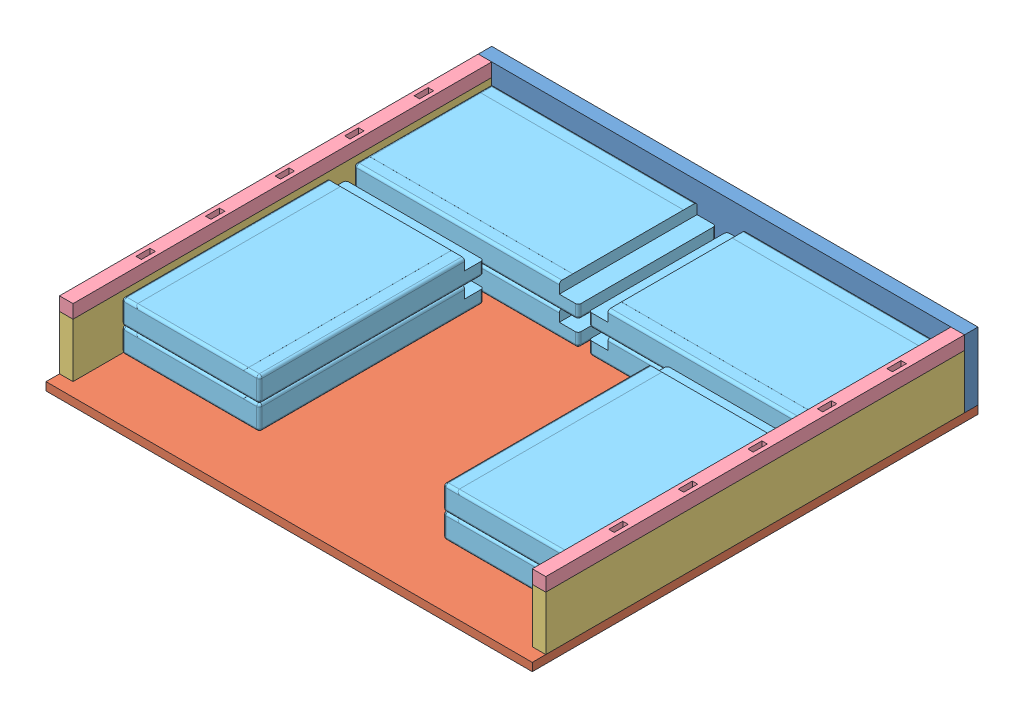
SolidWorks assembly Assem1, configuration Default. Lengths in mm.
Overall size (180 28 165).
14 component instances, 5 part files, 39 mates.
Components (placement in the parent):
- Back rail-1: Back rail [Default] at (72.2044 136.4605 98.1346) size (180 25 5)
- Bottom-1: Bottom [Default] at (72.2044 133.4605 178.1346) size (180 3 165)
- bottom of side rail-1: bottom of side rail [Default] at (-15.2956 156.4605 178.1346) x (0 0 -1) z (-1 0 0) size (155 20 5)
- top of side rail-1: top of side rail [Default] at (-14.7956 156.4605 178.1346) x (0 0 -1) z (1 0 0) size (155 5 5)
- bottom of side rail-2: bottom of side rail [Default] at (159.7044 136.4605 178.1346) x (0 0 -1) z (1 0 0) size (155 20 5)
- top of side rail-2: top of side rail [Default] at (160.2044 156.4605 178.1346) x (0 0 -1) z (1 0 0) size (155 5 5)
- Cell-1: Cell [Default] at (12.7044 136.4705 196.1346) x (-1 0 0) z (0 0 -1) size (51 9.02 83)
- Cell-2: Cell [Default] at (131.7044 145.4905 196.1346) x (-1 0 0) z (0 0 -1) size (51 9.02 83)
- Cell-3: Cell [Default] at (131.7044 136.4705 196.1346) x (-1 0 0) z (0 0 -1) size (51 9.02 83)
- Cell-4: Cell [Default] at (12.7044 145.4905 196.1346) x (-1 0 0) z (0 0 -1) size (51 9.02 83)
- Cell-5: Cell [Default] at (115.7044 136.4705 126.1346) x (0 0 1) z (-1 0 0) size (51 9.02 83)
- Cell-6: Cell [Default] at (115.7044 145.4905 126.1346) x (0 0 1) z (-1 0 0) size (51 9.02 83)
- Cell-7: Cell [Default] at (28.7044 145.4905 126.1346) x (0 0 -1) z (1 0 0) size (51 9.02 83)
- Cell-8: Cell [Default] at (28.7044 136.4705 126.1346) x (0 0 -1) z (1 0 0) size (51 9.02 83)
Mates (geometry in assembly coordinates):
- Coincident3: coincident anti-aligned: plane of Back rail-1 through (72.2044 136.4605 98.1346) normal (0 -1 0); plane of Bottom-1 through (72.2044 136.4605 178.1346) normal (0 1 0)
- Coincident4: coincident aligned: plane of Back rail-1 through (-17.7956 161.4605 95.6346) normal (0 0 -1); plane of Bottom-1 through (-17.7956 136.4605 95.6346) normal (0 0 -1)
- Coincident5: coincident anti-aligned: plane of bottom of side rail-1 through (-15.2956 156.4605 178.1346) normal (0 1 0); plane of top of side rail-1 through (-14.7956 156.4605 178.1346) normal (0 -1 0)
- Coincident6: coincident aligned: plane of bottom of side rail-1 through (-12.7956 136.4605 100.6346) normal (0 0 -1); plane of top of side rail-1 through (-17.7956 161.4605 100.6346) normal (0 0 -1)
- Coincident7: coincident aligned: plane of bottom of side rail-1 through (-17.7956 136.4605 255.6346) normal (-1 0 0); plane of top of side rail-1 through (-17.7956 161.4605 255.6346) normal (-1 0 0)
- Coincident9: coincident anti-aligned: plane of Bottom-1 through (72.2044 136.4605 178.1346) normal (0 1 0); plane of bottom of side rail-1 through (-15.2956 136.4605 178.1346) normal (0 -1 0)
- Coincident11: coincident aligned: plane of Bottom-1 through (-17.7956 136.4605 95.6346) normal (-1 0 0); plane of bottom of side rail-1 through (-17.7956 136.4605 255.6346) normal (-1 0 0)
- Coincident13: coincident anti-aligned: plane of bottom of side rail-2 through (159.7044 156.4605 178.1346) normal (0 1 0); plane of top of side rail-2 through (160.2044 156.4605 178.1346) normal (0 -1 0)
- Coincident14: coincident aligned: plane of bottom of side rail-2 through (157.2044 156.4605 255.6346) normal (0 0 1); plane of top of side rail-2 through (157.2044 161.4605 255.6346) normal (0 0 1)
- Coincident15: coincident aligned: plane of bottom of side rail-2 through (157.2044 156.4605 255.6346) normal (-1 0 0); plane of top of side rail-2 through (157.2044 161.4605 255.6346) normal (-1 0 0)
- Coincident16: coincident anti-aligned: plane of Bottom-1 through (72.2044 136.4605 178.1346) normal (0 1 0); plane of bottom of side rail-2 through (159.7044 136.4605 178.1346) normal (0 -1 0)
- Coincident17: coincident aligned: plane of Bottom-1 through (162.2044 136.4605 95.6346) normal (1 0 0); plane of bottom of side rail-2 through (162.2044 156.4605 255.6346) normal (1 0 0)
- Coincident18: coincident anti-aligned: plane of Back rail-1 through (-17.7956 161.4605 100.6346) normal (0 0 1); plane of bottom of side rail-2 through (157.2044 156.4605 100.6346) normal (0 0 -1)
- Coincident19: coincident aligned: plane of Bottom-1 through (-17.7956 136.4605 95.6346) normal (-1 0 0); plane of Back rail-1 through (-17.7956 161.4605 95.6346) normal (-1 0 0)
- Coincident20: coincident anti-aligned: plane of Back rail-1 through (-17.7956 161.4605 100.6346) normal (0 0 1); plane of bottom of side rail-1 through (-12.7956 136.4605 100.6346) normal (0 0 -1)
- Coincident21: coincident anti-aligned: plane of Cell-1 through (12.7044 145.4805 202.8086) normal (0 1 0); plane of Cell-4 through (12.7044 145.4805 202.8086) normal (0 -1 0)
- Coincident22: coincident aligned: plane of Cell-1 through (38.2044 145.4705 244.3086) normal (1 0 0); plane of Cell-4 through (38.2044 154.4905 244.3086) normal (1 0 0)
- Coincident23: coincident aligned: plane of Cell-1 through (38.2044 145.4705 244.3086) normal (0 0 1); plane of Cell-4 through (38.2044 154.4905 244.3086) normal (0 0 1)
- Coincident24: coincident anti-aligned: plane of Cell-2 through (131.7044 145.4805 196.1346) normal (0 -1 0); plane of Cell-3 through (131.7044 145.4805 196.1346) normal (0 1 0)
- Coincident25: coincident aligned: plane of Cell-2 through (157.2044 154.4905 237.6346) normal (1 0 0); plane of Cell-3 through (157.2044 145.4705 237.6346) normal (1 0 0)
- Coincident26: coincident aligned: plane of Cell-2 through (157.2044 154.4905 237.6346) normal (0 0 1); plane of Cell-3 through (157.2044 145.4705 237.6346) normal (0 0 1)
- Coincident27: coincident anti-aligned: plane of Bottom-1 through (72.2044 136.4605 178.1346) normal (0 1 0); plane of Cell-3 through (131.7044 136.4605 196.1346) normal (0 -1 0)
- Coincident28: coincident anti-aligned: plane of bottom of side rail-2 through (157.2044 156.4605 255.6346) normal (-1 0 0); plane of Cell-3 through (157.2044 145.4705 237.6346) normal (1 0 0)
- Coincident29: coincident anti-aligned: plane of Bottom-1 through (72.2044 136.4605 178.1346) normal (0 1 0); plane of Cell-1 through (12.7044 136.4605 202.8086) normal (0 -1 0)
- Coincident30: coincident anti-aligned: plane of bottom of side rail-1 through (-12.7956 136.4605 255.6346) normal (1 0 0); plane of Cell-4 through (-12.7956 154.4905 244.3086) normal (-1 0 0)
- Coincident31: coincident anti-aligned: plane of Cell-5 through (115.7044 145.4805 126.1346) normal (0 1 0); plane of Cell-6 through (115.7044 145.4805 126.1346) normal (0 -1 0)
- Coincident32: coincident aligned: plane of Cell-5 through (157.2044 145.4705 100.6346) normal (0 0 -1); plane of Cell-6 through (157.2044 154.4905 100.6346) normal (0 0 -1)
- Coincident33: coincident aligned: plane of Cell-5 through (157.2044 145.4705 100.6346) normal (1 0 0); plane of Cell-6 through (157.2044 154.4905 100.6346) normal (1 0 0)
- Coincident35: coincident anti-aligned: plane of Bottom-1 through (72.2044 136.4605 178.1346) normal (0 1 0); plane of Cell-5 through (115.7044 136.4605 126.1346) normal (0 -1 0)
- Coincident36: coincident anti-aligned: plane of Back rail-1 through (-17.7956 161.4605 100.6346) normal (0 0 1); plane of Cell-6 through (157.2044 154.4905 100.6346) normal (0 0 -1)
- Coincident37: coincident anti-aligned: plane of bottom of side rail-2 through (157.2044 156.4605 255.6346) normal (-1 0 0); plane of Cell-6 through (157.2044 154.4905 100.6346) normal (1 0 0)
- Distance1: distance = 3 mm anti-aligned: plane of Cell-2 through (157.2044 154.4905 154.6346) normal (0 0 -1); plane of Cell-6 through (157.2044 154.4905 151.6346) normal (0 0 1)
- Coincident39: coincident aligned: plane of Cell-7 through (-12.7956 154.4905 151.6346) normal (0 0 1); plane of Cell-8 through (-12.7956 145.4705 151.6346) normal (0 0 1)
- Coincident40: coincident anti-aligned: plane of Cell-7 through (28.7044 145.4805 126.1346) normal (0 -1 0); plane of Cell-8 through (28.7044 145.4805 126.1346) normal (0 1 0)
- Coincident41: coincident aligned: plane of Cell-7 through (-12.7956 154.4905 151.6346) normal (-1 0 0); plane of Cell-8 through (-12.7956 145.4705 151.6346) normal (-1 0 0)
- Coincident42: coincident anti-aligned: plane of Bottom-1 through (72.2044 136.4605 178.1346) normal (0 1 0); plane of Cell-8 through (28.7044 136.4605 126.1346) normal (0 -1 0)
- Coincident43: coincident anti-aligned: plane of Back rail-1 through (-17.7956 161.4605 100.6346) normal (0 0 1); plane of Cell-7 through (-12.7956 154.4905 100.6346) normal (0 0 -1)
- Coincident44: coincident anti-aligned: plane of bottom of side rail-1 through (-12.7956 136.4605 255.6346) normal (1 0 0); plane of Cell-7 through (-12.7956 154.4905 151.6346) normal (-1 0 0)
- Distance2: distance = 3 mm anti-aligned: plane of Cell-4 through (38.2044 154.4905 154.6346) normal (0 0 -1); plane of Cell-7 through (-12.7956 154.4905 151.6346) normal (0 0 1)
